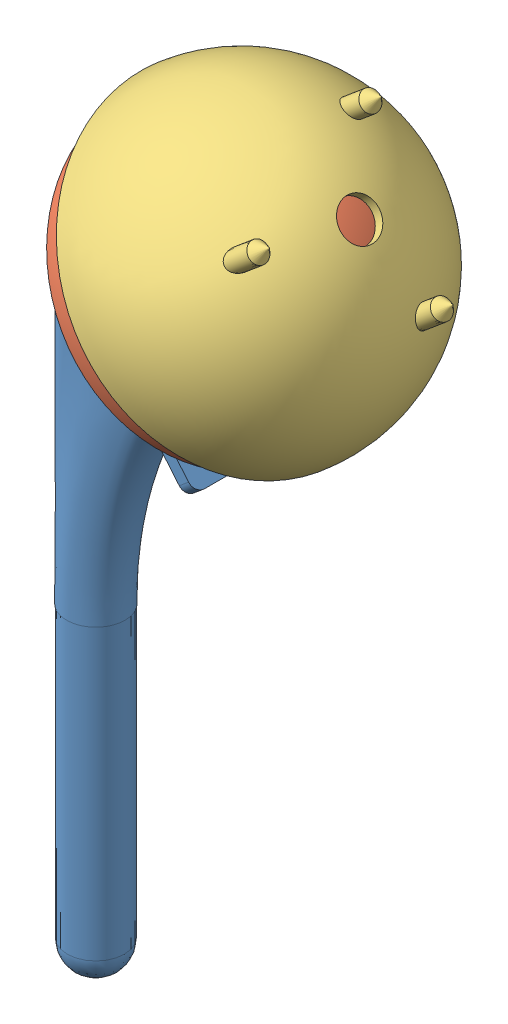
SolidWorks assembly Stem and Cup Assembly 6-2, configuration Default. Lengths in mm.
Overall size (112.64 246.05 104.19).
3 component instances, 3 part files, 4 mates.
Components (placement in the parent):
- Stem-1: Stem [Default] at (-157.2131 -174.4927 123.0171) size (71.48 203.79 50.8)
- Cup-1: Cup [Default] at (-119.2123 -3.5986 123.0171) x (0.018067 -0.021531 0.999605) z (0.642534 -0.765742 -0.028107) size (76.2 46.99 76.2)
- Cup Outer-1: Cup Outer [Default] at (-119.2123 -3.5986 123.0171) x (-0.21997 0.26215 -0.939623) z (0.603978 -0.719793 -0.342213) size (81.28 43.18 81.28)
Mates (geometry in assembly coordinates):
- Concentric2: concentric: sphere of Cup-1; sphere of Cup Outer-1
- Parallel2: parallel aligned: plane of Cup-1 through (-126.0225 -9.313 123.0171) normal (-0.766044 -0.642788 0); plane of Cup Outer-1 through (-127.5932 6.3893 87.2175) normal (-0.766044 -0.642788 0)
- Concentric3: concentric: sphere of Stem-1; sphere of Cup-1
- Parallel3: parallel anti-aligned: plane of Stem-1 through (-150.356 -22.0021 116.4047) normal (0.766044 0.642788 0); plane of Cup-1 through (-126.0225 -9.313 123.0171) normal (-0.766044 -0.642788 0)
